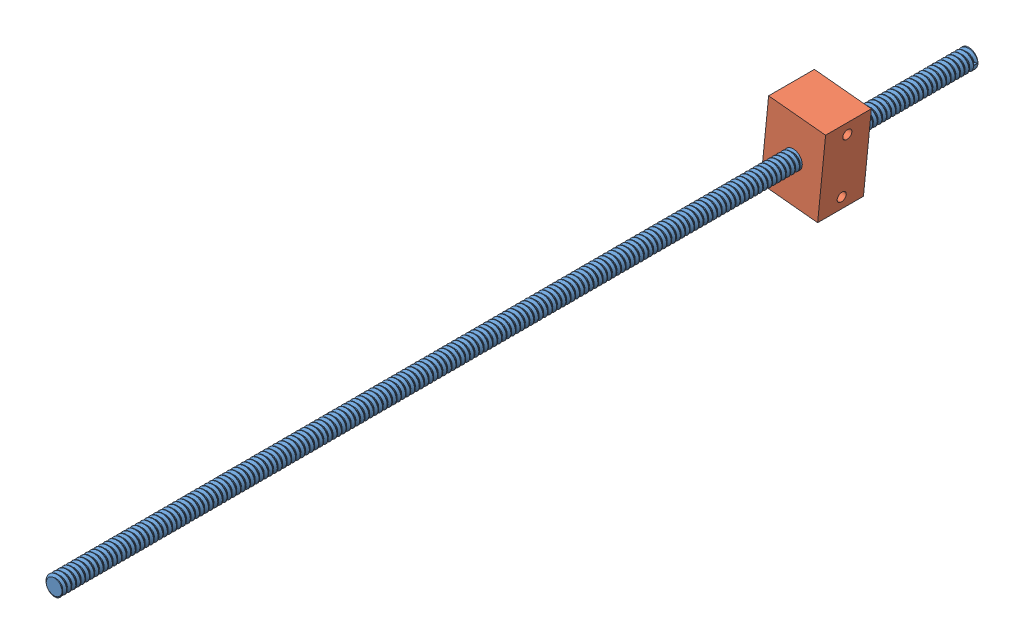
SolidWorks assembly Assem1, configuration Default. Lengths in mm.
Overall size (28.33 37.3 401.75).
2 component instances, 2 part files, 1 mates.
Components (placement in the parent):
- screw rod + bossa-1: screw rod + bossa [Default] at (-64.1445 14.4678 -176.9107) size (8.21 9.24 401.75)
- housing-1: housing [Default] at (-64.1445 14.4678 -120.1785) x (0.098732 0.995114 0) z (0 0 1) size (35 25 20)
Mates (geometry in assembly coordinates):
- Screw1: screw = 2: cylinder of assembly; cylinder of assembly; cylinder of screw rod + bossa-1 through (-64.1445 14.4678 223.0893) axis (0 0 -1) radius 4; cylinder of housing-1 through (-64.1445 14.4678 -120.1785) axis (0 0 1) radius 4
